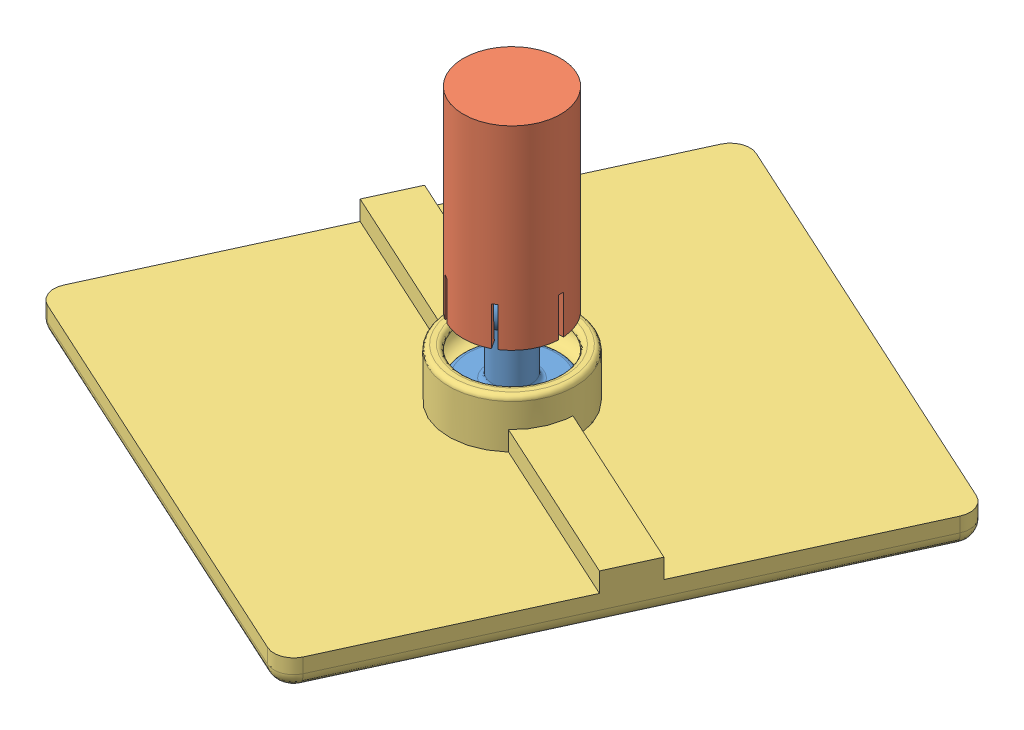
SolidWorks assembly Wang-SolarPowerSystem, configuration Default. Lengths in mm.
Overall size (68.37 31 70.83).
3 component instances, 3 part files, 4 mates.
Components (placement in the parent):
- BallCasterJoyStick-2: BallCasterJoyStick [Default] at origin size (10 12 10)
- SolarPanelMount-2: SolarPanelMount [Default] at (0 6 0) x (-0.201104 0 0.97957) z (0.97957 0 0.201104) size (10 20 10)
- Solar Panel-3: Solar Panel [Default] at (22.7267 -2 10.4162) x (-0.909069 0 -0.416646) z (-0.416646 0 0.909069) size (50 8 55)
Mates (geometry in assembly coordinates):
- Coincident15: coincident anti-aligned: plane of BallCasterJoyStick-2 through (0 -2 0) normal (0 -1 0); plane of Solar Panel-3 through (11.2689 -2 35.4155) normal (0 1 0)
- Concentric1: concentric anti-aligned: cylinder of BallCasterJoyStick-2 through (0 14.7525 0) axis (0 1 0) radius 5; cylinder of Solar Panel-3 through (0 3 0) axis (0 -1 0) radius 5
- Concentric4: concentric anti-aligned: circle of BallCasterJoyStick-2; circle of SolarPanelMount-2
- Coincident18: coincident anti-aligned: plane of BallCasterJoyStick-2 through (0 10 0) normal (0 1 0); plane of SolarPanelMount-2 through (0 10 0) normal (0 -1 0)
